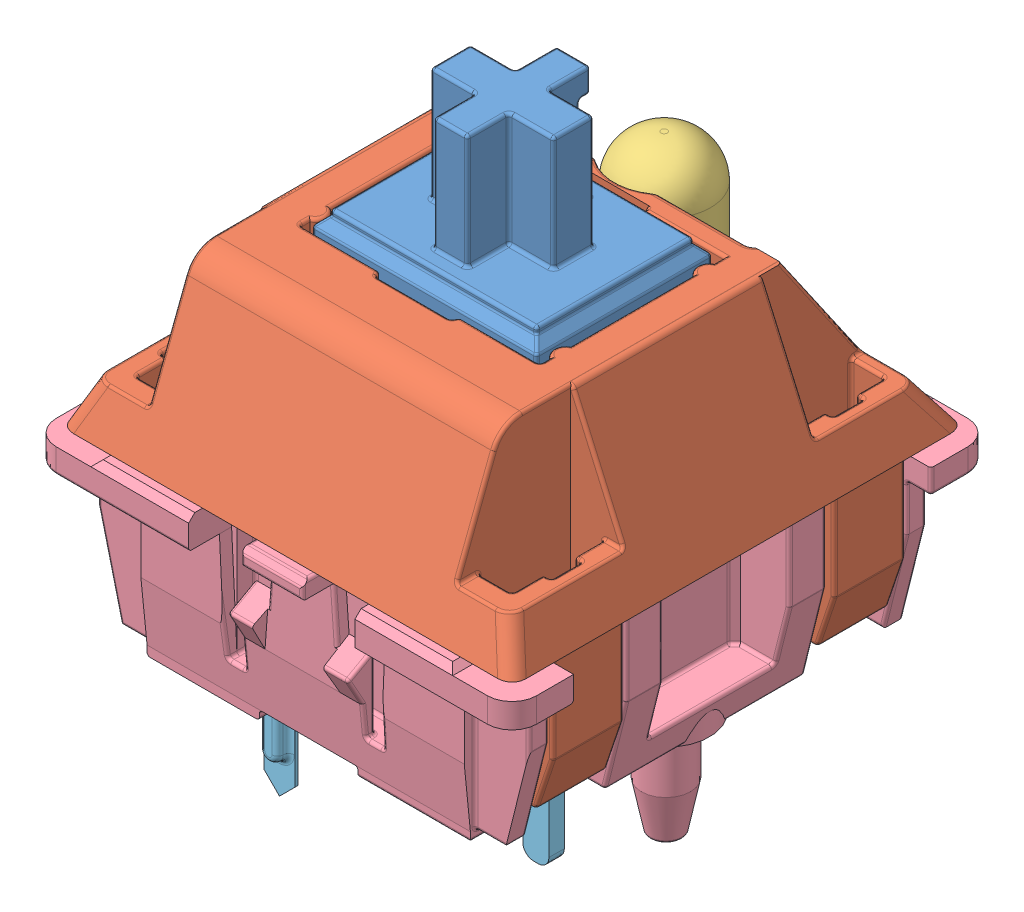
SolidWorks assembly MX 按键, configuration Default. Lengths in mm.
Overall size (15.6 18.9 15.6).
6 component instances, 6 part files, 8 mates.
Components (placement in the parent):
- MX 轴 按键-1: MX 轴 按键 [Default] at (7.35 2 -7.35) size (8.9 10.4 5.7)
- MX 轴 轴体-1: MX 轴 轴体 [Default] at origin size (14.7 9.91 14.7)
- MX轴 无帽LED-1: MX轴 无帽LED [Default] at (7.35 0.5 -12.292) size (3 15.3 3)
- 机箱用方开关键帽 1574-1: 机箱用方开关键帽 1574 [Default] at (7.35 5.7 -7.35) (suppressed, hidden)
- MX轴 轴体 底部-1: MX轴 轴体 底部 [默认] at (7.35 -0.2 -7.35) size (15.6 12.5 15.6)
- 针脚-2: 针脚 [默认] at (-5.5727 -8.7 12.741) size (7.15 6.7 2.96)
Mates (geometry in assembly coordinates):
- Distance1: distance = 0.15 mm anti-aligned: plane of MX 轴 轴体-1 through (3.45 1.4 -4.35) normal (0 0 -1); plane of MX 轴 按键-1 through (3.7 5.2 -4.5) normal (0 0 1)
- Distance2: distance = 0.25 mm anti-aligned: plane of MX 轴 轴体-1 through (3.45 1.4 -10.35) normal (1 0 0); plane of MX 轴 按键-1 through (3.7 5.2 -10.2) normal (-1 0 0)
- Coincident4: coincident anti-aligned: plane of MX 轴 轴体-1 through (0 0 0) normal (0 -1 0); plane of MX轴 轴体 底部-1 through (7.35 0 -7.35) normal (0 1 0)
- LimitDistance2: limit distance = -0.5 mm aligned: plane of MX 轴 按键-1 through (7.35 5.7 -7.35) normal (0 1 0); plane of MX 轴 轴体-1 through (0 5.2 0) normal (0 1 0)
- Coincident10: coincident anti-aligned: plane of MX轴 轴体 底部-1 through (10.6 -0.9 -4.95) normal (0 0 1); plane of 针脚-2 through (10.6 -2.5 -4.95) normal (0 0 -1)
- Coincident11: coincident anti-aligned: plane of MX轴 轴体 底部-1 through (10.6 -0.9 -4.95) normal (1 0 0); plane of 针脚-2 through (10.6 -2.5 -4.95) normal (-1 0 0)
- Concentric1: concentric anti-aligned: cylinder of MX 轴 轴体-1 through (7.35 0.5 -12.292) axis (0 1 0) radius 1.6; cylinder of MX轴 无帽LED-1 through (7.35 5.8 -12.292) axis (0 -1 0) radius 1.5
- Coincident12: coincident anti-aligned: plane of MX 轴 轴体-1 through (7.35 0.5 -12.292) normal (0 1 0); plane of MX轴 无帽LED-1 through (7.35 0.5 -12.292) normal (0 -1 0)
